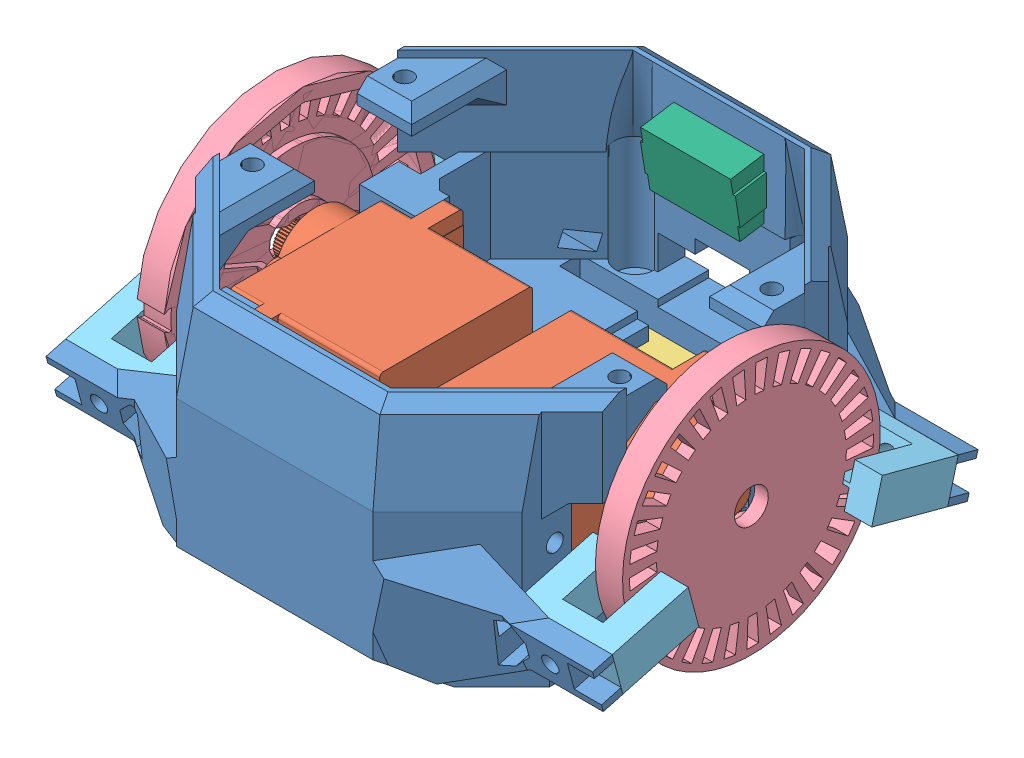
SolidWorks assembly assem, configuration Default. Lengths in mm.
Overall size (80.6 49.16 70.99).
13 component instances, 8 part files, 30 mates.
Components (placement in the parent):
- base-1: base [Default] at origin size (80.6 35.01 70)
- sg90-1: sg90 [Varsayılan] at (-3 16 5.25) x (0 1 0) z (0 0 1) size (12 30 32.01)
- sg90-3: sg90 [Varsayılan] at (3 16 5.25) x (0 -1 0) z (0 0 1) size (12 30 32.01)
- 503450-1: 503450 [503450] at (-0.5202 0 0.2836) x (0 0 -1) z (1 0 0) size (53 5 38)
- wheel40-1: wheel40 [Default] at (35.3 16 0) x (0 -0.36119 -0.932492) z (-1 0 0) size (38 38 4)
- photo_interrupter-1: photo_interrupter [Default] at (-33.275 7.9728 18.3476) x (1 0 0) z (0 0.965926 0.258819) size (14.05 11.6 6.03)
- photo_interrupter-2: photo_interrupter [Default] at (33.275 7.9728 18.3476) x (1 0 0) z (0 0.965926 0.258819) size (14.05 11.6 6.03)
- photo_interrupter-3: photo_interrupter [Default] at (33.275 13.778 -19.9031) x (1 0 0) z (0 -0.965926 0.258819) size (14.05 11.6 6.03)
- photo_interrupter-4: photo_interrupter [Default] at (-33.275 13.7973 -19.9083) x (1 0 0) z (0 -0.965926 0.258819) size (14.05 11.6 6.03)
- wheel40-2: wheel40 [Default] at (-35.3 16 0) x (0 -0.36119 -0.932492) z (1 0 0) size (38 38 4)
- circ_correct_dim-1: circ_correct_dim [Default] at (-29.9836 34.5 29.944) size (59.94 2.54 59.94) (hidden)
- STACK_ASM-2: STACK_ASM [Default] at (-72.316 -8.1974 -5.4322) x (1 0 0) z (0 1 0) size (59.9 59.95 39.03) (hidden)
- on_off-1: on_off [Default] at (0 27.5233 -34.1842) x (1 0 0) z (0 -0.156434 0.987688) size (14.8 10.4 9)
Mates (geometry in assembly coordinates):
- Parallel1: parallel aligned: plane of base-1 through (0 22 0) normal (0 1 0); plane of sg90-1 through (-4 22 -5.5) normal (0 1 0)
- Parallel2: parallel aligned: plane of sg90-1 through (-3 21.5 16) normal (1 0 0); plane of assembly through (0 0 0) normal (1 0 0)
- Distance1: distance = 16 mm: line of sg90-1 through (-33 16 0.75) axis (0 0 -1); plane of base-1 through (0 0 0) normal (0 -1 0)
- Coincident4: coincident aligned: plane of base-1 through (0 0 0) normal (0 0 1); plane of assembly through (0 0 0) normal (0 0 1)
- Coincident6: coincident aligned: plane of base-1 through (0 0 0) normal (1 0 0); plane of assembly through (0 0 0) normal (1 0 0)
- Coincident10: coincident: line of sg90-1 through (-33 16.75 0) axis (0 -1 0); plane of assembly through (0 0 0) normal (0 0 1)
- Distance2: distance = 4.3 mm anti-aligned: plane of wheel40-1 through (33.3 16 0) normal (-1 0 0); plane of sg90-3 through (29 16 3) normal (1 0 0)
- Concentric1: concentric: cylinder of sg90-3 through (28 16 0) axis (-1 0 0) radius 6; cylinder of wheel40-1 through (31.3 16 0) axis (1 0 0) radius 20
- Coincident21: coincident anti-aligned: plane of base-1 through (20.5 7 -11.3027) normal (-1 0 0); plane of sg90-3 through (20.5 10.5 20.75) normal (1 0 0)
- Coincident22: coincident anti-aligned: plane of base-1 through (40.3 12.2962 25.5106) normal (0 0.258819 -0.965926); plane of photo_interrupter-2 through (26.25 12.2962 25.5106) normal (0 -0.258819 0.965926)
- Coincident23: coincident aligned: plane of base-1 through (40.3 0 0) normal (1 0 0); plane of photo_interrupter-2 through (40.3 12.2962 25.5106) normal (1 0 0)
- Coincident24: coincident aligned: plane of base-1 through (40.3 12.2962 25.5106) normal (0 0.965926 0.258819); plane of photo_interrupter-2 through (33.275 13.7973 19.9083) normal (0 0.965926 0.258819)
- Coincident25: coincident anti-aligned: plane of base-1 through (40.3 12.2962 -25.5106) normal (0 0.258819 0.965926); plane of photo_interrupter-3 through (26.25 6.4523 -23.9448) normal (0 -0.258819 -0.965926)
- Coincident26: coincident aligned: plane of base-1 through (40.3 0 0) normal (1 0 0); plane of photo_interrupter-3 through (40.3 6.4523 -23.9448) normal (1 0 0)
- Coincident27: coincident aligned: plane of base-1 through (40.3 6.4523 -23.9448) normal (0 -0.965926 0.258819); plane of photo_interrupter-3 through (33.275 7.9535 -18.3424) normal (0 -0.965926 0.258819)
- Coincident28: coincident anti-aligned: plane of base-1 through (-40.3 12.2962 25.5106) normal (0 0.258819 -0.965926); plane of photo_interrupter-1 through (-40.3 12.2962 25.5106) normal (0 -0.258819 0.965926)
- Coincident29: coincident aligned: plane of base-1 through (-40.3 0 0) normal (-1 0 0); plane of photo_interrupter-1 through (-40.3 12.2962 25.5106) normal (-1 0 0)
- Coincident30: coincident aligned: plane of base-1 through (-40.3 12.2962 25.5106) normal (0 0.965926 0.258819); plane of photo_interrupter-1 through (-33.275 13.7973 19.9083) normal (0 0.965926 0.258819)
- Coincident31: coincident aligned: plane of base-1 through (-40.3 0 0) normal (-1 0 0); plane of photo_interrupter-4 through (-40.3 6.4716 -23.9499) normal (-1 0 0)
- Coincident33: coincident anti-aligned: plane of base-1 through (-40.3 12.2962 -25.5106) normal (0 0.258819 0.965926); plane of photo_interrupter-4 through (-40.3 6.4716 -23.9499) normal (0 -0.258819 -0.965926)
- Coincident34: coincident aligned: plane of base-1 through (-40.3 12.2962 -25.5106) normal (0 0.965926 -0.258819); plane of photo_interrupter-4 through (-33.275 13.7973 -19.9083) normal (0 0.965926 -0.258819)
- Parallel3: parallel anti-aligned: plane of base-1 through (0 5 0) normal (0 -1 0); plane of 503450-1 through (-0.5202 5 0.2836) normal (0 1 0)
- Coincident36: coincident anti-aligned: plane of base-1 through (0 5 0) normal (0 -1 0); plane of 503450-1 through (-0.5202 5 0.2836) normal (0 1 0)
- Distance8: distance = 1 mm anti-aligned: plane of circ_correct_dim-1 through (-29.9836 37.04 -30) normal (0 0 -1); plane of base-1 through (14.4975 22 -31) normal (0 0 1)
- Distance9: distance = 1 mm: point of circ_correct_dim-1; plane of base-1 through (-11.669 22 -32.1716) normal (0.707107 0 0.707107)
- Parallel4: parallel aligned: plane of base-1 through (0 22 0) normal (0 1 0); plane of circ_correct_dim-1 through (-29.9836 37.04 29.944) normal (0 1 0)
- Concentric2: concentric aligned: cylinder of base-1 through (-27.0836 35 -11.2416) axis (0 1 0) radius 1.25; cylinder of STACK_ASM-2 through (-27.0836 34.0111 -11.2416) axis (0 1 0) radius 1.6055
- Parallel6: parallel anti-aligned: plane of base-1 through (0 35 -33) normal (0 0.156434 -0.987688); plane of on_off-1 through (0 26.2718 -26.2827) normal (0 -0.156434 0.987688)
- Coincident40: coincident anti-aligned: plane of base-1 through (0 35 -33) normal (0 0.156434 -0.987688); plane of on_off-1 through (0 27.5233 -34.1842) normal (0 -0.156434 0.987688)
- Coincident41: coincident aligned: plane of on_off-1 through (0 27.5233 -34.1842) normal (1 0 0)
